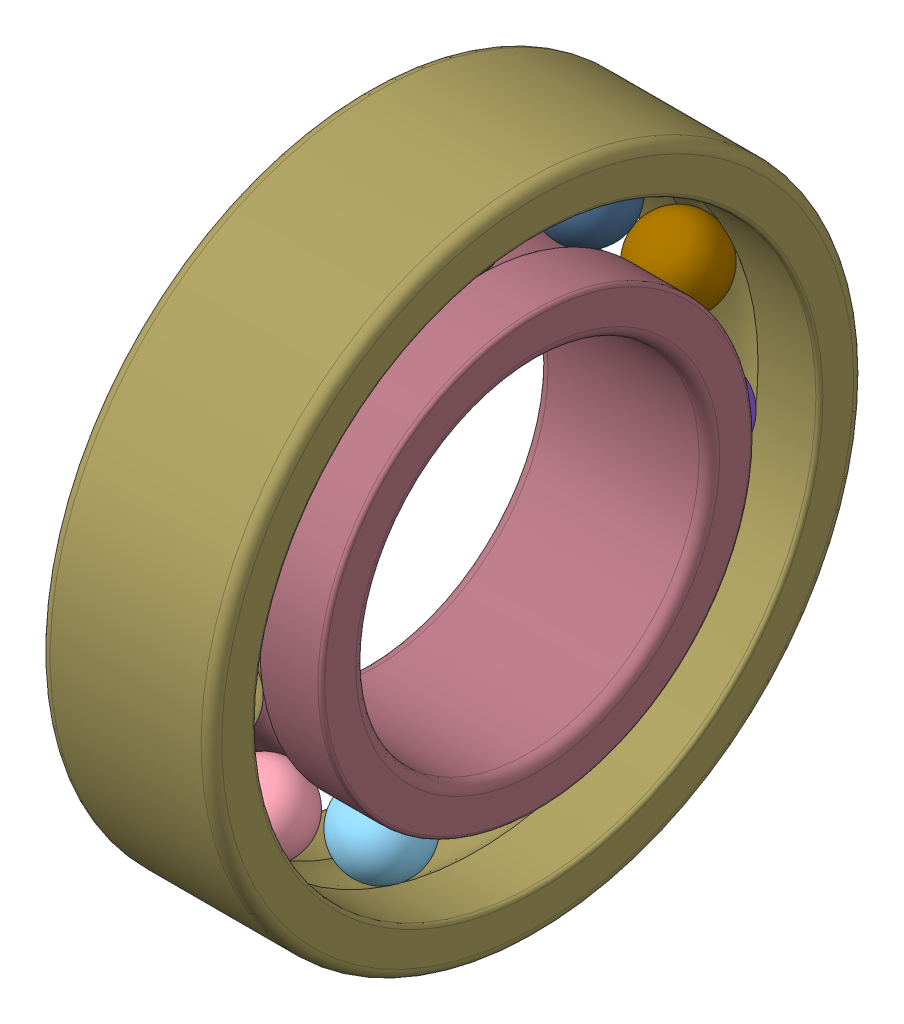
SolidWorks assembly ballBearing2, configuration Défaut. Lengths in mm.
Overall size (5.01 19 19).
13 component instances, 13 part files, 0 mates.
Components (placement in the parent):
- ball-1: ball [Défaut] at (2.5 6.0991 3.9196) size (3.2 3.01 3.02)
- ball_2-1: ball_2 [Défaut] at (2.5 3.0118 6.5948) size (3.23 3.28 3.31)
- ball_3-1: ball_3 [Défaut] at (2.5 -1.0318 7.1762) size (3.31 3.03 3.32)
- ball_4-1: ball_4 [Défaut] at (2.5 -4.7477 5.4792) size (3.18 3.13 3.12)
- ball_5-1: ball_5 [Défaut] at (2.5 -6.9563 2.0426) size (3.11 3.23 3.11)
- ball_6-1: ball_6 [Défaut] at (2.5 -6.9563 -2.0426) size (3.2 3.24 3.25)
- ball_7-1: ball_7 [Défaut] at (2.5 -4.7477 -5.4792) size (3.13 3.32 3.2)
- ball_8-1: ball_8 [Défaut] at (2.5 -1.0318 -7.1762) size (3.23 3.19 3.29)
- ball_9-1: ball_9 [Défaut] at (2.5 3.0118 -6.5948) size (3.19 2.92 2.97)
- ball_10-1: ball_10 [Défaut] at (2.5 6.0991 -3.9196) size (3.19 2.92 2.97)
- ball_11-1: ball_11 [Défaut] at (2.5 7.25 0) size (3.28 3.11 3.26)
- external_bearing_ring-1: external_bearing_ring [Défaut] at (2.5 0 0) size (5 19 19)
- internal_bearing_ring-1: internal_bearing_ring [Défaut] at (2.5 0 0) size (5.01 12.6 12.6)
